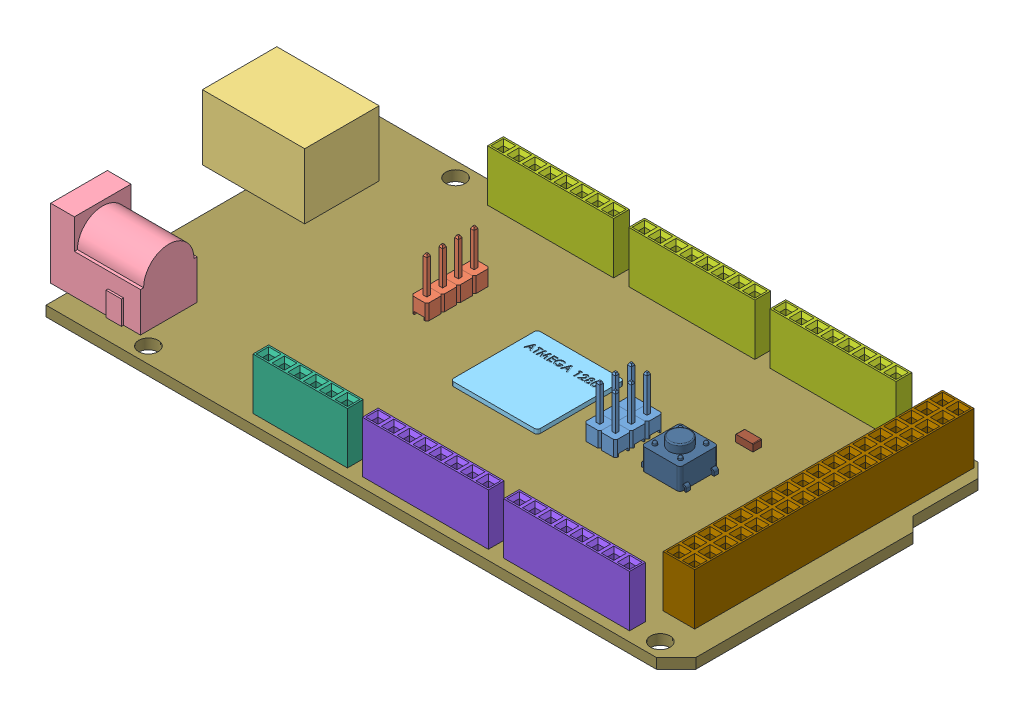
SolidWorks assembly Arduino Mega Rev-3, configuration Default. Lengths in mm.
Overall size (108.58 14.9 53.21).
23 component instances, 12 part files, 0 mates.
Components (placement in the parent):
- Part4-1: Part4 [Default] at origin size (2.54 9.3 2.54)
- Part20-13: Part20 [Default] at origin size (2.54 9.3 2.54)
- Part24-1: Part24 [Default] at origin size (16.5 14.22 14.86)
- Part26-1: Part26 [Default] at origin size (14.48 14.78 9.47)
- Part28-1: Part28 [Default] at origin size (14 0.7 14)
- Part30-1: Part30 [Default] at origin size (15.24 8.3 2.54)
- Part32-1: Part32 [Default] at origin size (20.32 8.3 2.54)
- Part40-3: Part40 [Default] at origin size (20.32 8.3 2.54)
- Part42-1: Part42 [Default] at origin size (5.08 8.3 45.04)
- Part44-1: Part44 [Default] at origin size (7.9 7.35 6.2)
- Part46-1: Part46 [Default] at origin size (2.8 1.12 1.4)
- PCB-FIXED-1: PCB-FIXED [Default] at (0.1155 -4.6912 4.2705) x (1 0 0) z (0 0 -1) size (101.6 1.65 53.21)
- Part4-7: Part4 [Default] at (-2.54 0 0) size (2.54 9.3 2.54)
- Part4-8: Part4 [Default] at (0 0 -2.54) size (2.54 9.3 2.54)
- Part4-9: Part4 [Default] at (-2.54 0 -2.54) size (2.54 9.3 2.54)
- Part4-10: Part4 [Default] at (0 0 -5.08) size (2.54 9.3 2.54)
- Part4-11: Part4 [Default] at (-2.54 0 -5.08) size (2.54 9.3 2.54)
- Part20-14: Part20 [Default] at (0 0 -2.54) size (2.54 9.3 2.54)
- Part20-15: Part20 [Default] at (0 0 -5.08) size (2.54 9.3 2.54)
- Part20-16: Part20 [Default] at (0 0 -7.62) size (2.54 9.3 2.54)
- Part32-6: Part32 [Default] at (-22.77 0 0) size (20.32 8.3 2.54)
- Part32-7: Part32 [Default] at (-45.54 0 0) size (20.32 8.3 2.54)
- Part40-4: Part40 [Default] at (-22.77 0 0) size (20.32 8.3 2.54)
